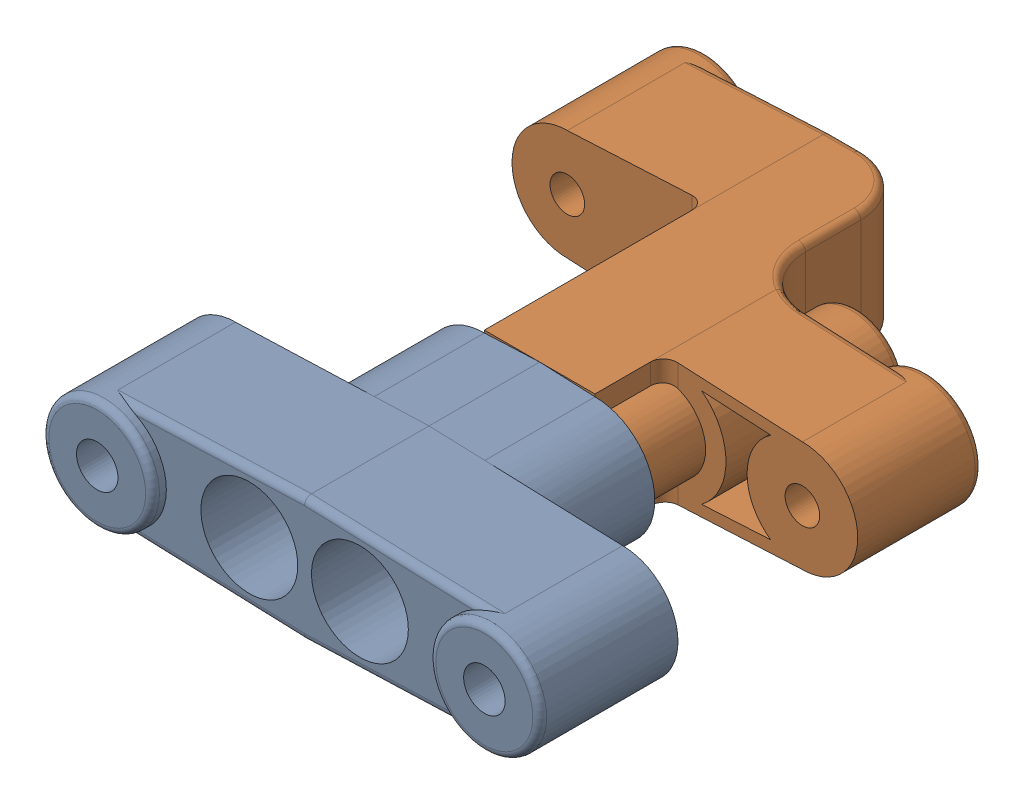
SolidWorks assembly Triangle avant, configuration Défaut. Lengths in mm.
Overall size (36 9.06 44).
4 component instances, 3 part files, 7 mates.
Components (placement in the parent):
- Triangle avant-C16-1: Triangle avant-C16 [Défaut] at origin size (36 9 18)
- Triangle avant-C17-1: Triangle avant-C17 [Défaut] at (0 0 -8) x (1 0 0) z (0 0 -1) size (36 9.06 34)
- Vis-M3-10-1: Vis-M3-10 [Défaut] at (-4 0 1) size (4.92 4.92 11.54)
- Vis-M3-10-2: Vis-M3-10 [Défaut] at (4 0 1) size (4.92 4.92 11.54)
Mates (geometry in assembly coordinates):
- Coïncidente1: coincident aligned: axis of Triangle avant-C16-1 through (4 0 0) axis (0 0 1); axis of Triangle avant-C17-1 through (4 0 -8.5) axis (0 0 1)
- Coïncidente2: coincident aligned: axis of Triangle avant-C16-1 through (-4 0 1) axis (0 0 1); axis of Triangle avant-C17-1 through (-4 0 -24) axis (0 0 1)
- Coïncidente3: coincident anti-aligned: plane of Triangle avant-C16-1 through (-4 0 -8) normal (0 0 -1); plane of Triangle avant-C17-1 through (-4 0 -8) normal (0 0 1)
- Coïncidente4: coincident anti-aligned: plane of Triangle avant-C16-1 through (-4 0 1) normal (0 0 1); plane of Vis-M3-10-1
- Coïncidente5: coincident aligned: axis of Triangle avant-C17-1 through (-4 0 -8.5) axis (0 0 1); axis of Vis-M3-10-1 through (-4 0 -8.5) axis (0 0 1)
- Coïncidente6: coincident anti-aligned: plane of Triangle avant-C16-1 through (4 0 1) normal (0 0 1); plane of Vis-M3-10-2
- Coïncidente7: coincident aligned: axis of Triangle avant-C17-1 through (4 0 -13) axis (0 0 1); axis of Vis-M3-10-2 through (4 0 -8.5) axis (0 0 1)
